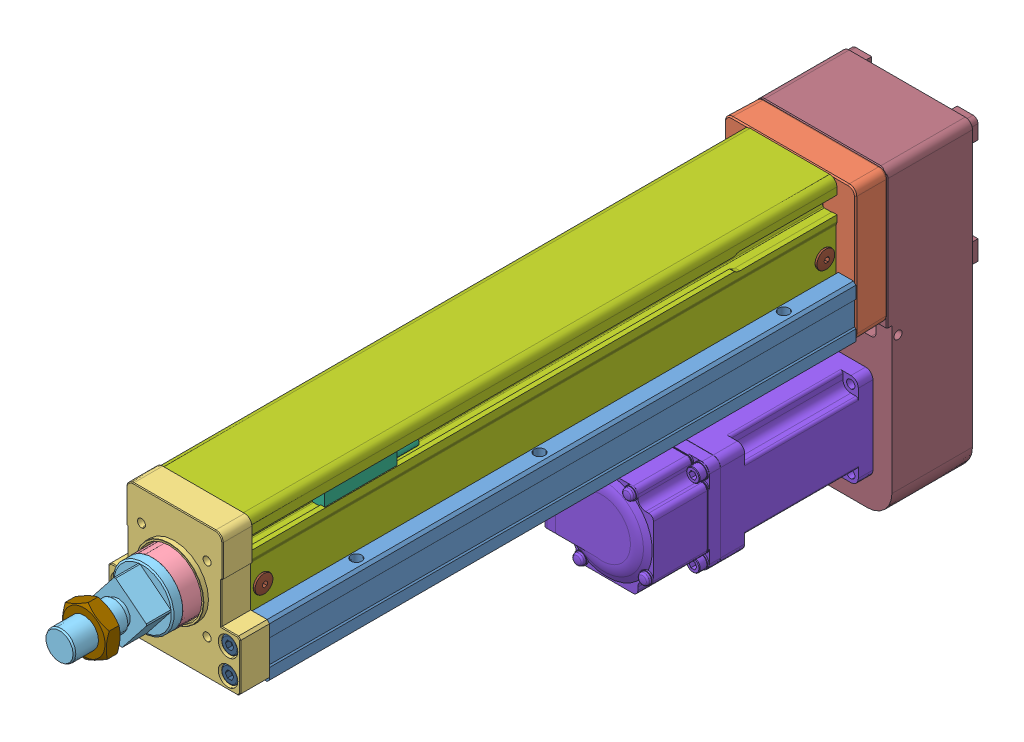
SolidWorks assembly Y5-BM-100W, configuration Default. Lengths in mm.
Overall size (128.79 125.85 350).
25 component instances, 14 part files, 57 mates.
Components (placement in the parent):
- 底座GY5^Y5-BM-100W-1: 底座GY5^Y5-BM-100W [默认] at (172.2343 500.0265 205.4117) x (1 0 0) z (0 -1 0) size (54 240 25) (virtual)
- 丝杆座板GY5^Y5-BM-100W-1: 丝杆座板GY5^Y5-BM-100W [默认] at (172.2343 515.5765 191.9117) size (54.09 55.09 28) (virtual)
- 轴承座Y5^Y5-BM-100W-1: 轴承座Y5^Y5-BM-100W [Default] at (172.2343 516.7765 445.4117) size (54 54 22) (virtual)
- 推杆Y5^Y5-BM-100W-1: 推杆Y5^Y5-BM-100W [Default] at (172.2343 516.7765 316.4117) x (-0.030388 -0.999538 0) z (-0.999538 0.030388 0) size (25 150 25) (virtual)
- 螺纹连接头Y5^Y5-BM-100W-1: 螺纹连接头Y5^Y5-BM-100W [Default] at (172.2343 516.7765 470.4117) x (-0.620248 -0.784406 0) z (0 0 -1) size (25 25 47) (virtual)
- 磁性感应开关^Y5-BM-100W-2: 磁性感应开关^Y5-BM-100W [默认] at (153.1454 533.4018 308.9117) x (-1 0 0) z (0 0 -1) size (5 6.3 39.5) (virtual)
- 上盖Y5^Y5-BM-100W-1: 上盖Y5^Y5-BM-100W [Default] at (153.6454 513.9765 205.4117) size (38.57 34 240) (virtual)
- 松下100W电机MSMF012L1U2^Y5-BM-100W-1: 松下100W电机MSMF012L1U2^Y5-BM-100W [默认] at (172.2343 447.7765 190.4117) x (0 0 -1) z (0 1 0) size (118.87 120.84 38.2) (virtual)
- 磁性感应开关^Y5-BM-100W-3: 磁性感应开关^Y5-BM-100W [默认] at (153.1454 533.4018 269.4117) x (-1 0 0) z (0 0 -1) size (5 6.3 39.5) (virtual)
- 磁性感应开关^Y5-BM-100W-4: 磁性感应开关^Y5-BM-100W [默认] at (191.3174 533.4018 385.4117) x (1 0 0) z (0 0 -1) size (5 6.3 39.5) (virtual)
- 六角薄螺母M12×1.25^Y5-BM-100W-1: 六角薄螺母M12×1.25^Y5-BM-100W [默认] at (172.2343 516.7765 494.4117) x (0.828588 -0.559859 0) z (0 0 1) size (20.78 18 6) (virtual)
- hexagon socket head cap screws gb-6: hexagon socket head cap screws gb [GB_FASTENER_SCREWS_HSHCS M4X12-N] at (194.2343 504.2765 456.8117) x (0 0 -1) z (1 0 0) size (16 7 7)
- hexagon socket head cap screws gb-7: hexagon socket head cap screws gb [GB_FASTENER_SCREWS_HSHCS M4X12-N] at (194.2343 493.7765 456.8117) x (0 0 -1) z (1 0 0) size (16 7 7)
- hexagon socket head cap screws gb-8: hexagon socket head cap screws gb [GB_FASTENER_SCREWS_HSHCS M4X12-N] at (150.2343 493.7765 456.8117) x (0 0 -1) z (1 0 0) size (16 7 7)
- hexagon socket head cap screws gb-9: hexagon socket head cap screws gb [GB_FASTENER_SCREWS_HSHCS M4X12-N] at (150.2343 504.2765 456.8117) x (0 0 -1) z (1 0 0) size (16 7 7)
- 内六角螺丝M3X5^Y5-BM-100W-1: 内六角螺丝M3X5^Y5-BM-100W [默认] at (186.1785 516.7765 210.4117) x (0 -1 0) z (0 0 1) size (7.5 6.19 7.5) (virtual)
- 内六角螺丝M3X5^Y5-BM-100W-2: 内六角螺丝M3X5^Y5-BM-100W [默认] at (186.1785 516.7765 440.4117) x (0 -0.21215 -0.977237) z (0 -0.977237 0.21215) size (7.5 6.19 7.5) (virtual)
- 内六角螺丝M3X5^Y5-BM-100W-3: 内六角螺丝M3X5^Y5-BM-100W [默认] at (158.2843 516.7765 440.4117) x (0 0.554408 0.832245) z (0 -0.832245 0.554408) size (7.5 6.19 7.5) (virtual)
- 内六角螺丝M3X5^Y5-BM-100W-4: 内六角螺丝M3X5^Y5-BM-100W [默认] at (158.2843 516.7765 210.4117) x (0 -0.497668 -0.867368) z (0 0.867368 -0.497668) size (7.5 6.19 7.5) (virtual)
- 304电机盖板Y5^Y5-BM-100W-1: 304电机盖板Y5^Y5-BM-100W [默认] at (172.2343 480.0265 157.4117) x (-1 0 0) z (0 -1 0) size (51.5 1 123.5) (virtual)
- 电机板Y5-BLRM-P38^Y5-BM-100W-1: 电机板Y5-BLRM-P38^Y5-BM-100W [默认] at (171.4843 468.5765 205.4117) x (0 0 1) z (-1 0 0) size (38 125.5 53.5) (virtual)
- hexagon socket button head screws gb-7: hexagon socket button head screws gb [GB_SOCKET_TYPE7 M3X6-N] at (159.7343 423.7765 154.7617) x (0 0 1) z (-1 0 0) size (7.65 5.7 5.7)
- hexagon socket button head screws gb-8: hexagon socket button head screws gb [GB_SOCKET_TYPE7 M3X6-N] at (184.7343 423.7765 154.7617) x (0 0 1) z (-1 0 0) size (7.65 5.7 5.7)
- hexagon socket button head screws gb-9: hexagon socket button head screws gb [GB_SOCKET_TYPE7 M3X6-N] at (159.7343 536.7765 154.7617) x (0 0 1) z (-1 0 0) size (7.65 5.7 5.7)
- hexagon socket button head screws gb-10: hexagon socket button head screws gb [GB_SOCKET_TYPE7 M3X6-N] at (184.7343 536.7765 154.7617) x (0 0 1) z (-1 0 0) size (7.65 5.7 5.7)
Mates (geometry in assembly coordinates):
- 同心129: concentric: cylinder of 推杆Y5^Y5-BM-100W-1 through (172.2343 516.7765 466.4117) axis (0 0 -1) radius 8.5; cylinder of 螺纹连接头Y5^Y5-BM-100W-1 through (172.2343 516.7765 457.4117) axis (0 0 1) radius 10
- 重合133: coincident: plane of 推杆Y5^Y5-BM-100W-1 through (172.2343 516.7765 466.4117) normal (0 0 1); plane of 螺纹连接头Y5^Y5-BM-100W-1 through (172.2343 516.7765 466.4117) normal (0 0 -1)
- 同心133: concentric: cylinder of 底座GY5^Y5-BM-100W-1 through (194.2343 493.7765 445.4117) axis (0 0 1) radius 1.65; cylinder of 轴承座Y5^Y5-BM-100W-1 through (194.2343 493.7765 457.4117) axis (0 0 1) radius 2.25
- 重合134: coincident: plane of 底座GY5^Y5-BM-100W-1 through (167.2343 487.8265 445.4117) normal (0 0 1); plane of 轴承座Y5^Y5-BM-100W-1 through (172.2343 516.7765 445.4117) normal (0 0 -1)
- 同心136: concentric: cylinder of 底座GY5^Y5-BM-100W-1 through (150.2343 504.2765 445.4117) axis (0 0 1) radius 1.65; cylinder of 轴承座Y5^Y5-BM-100W-1 through (150.2343 504.2765 457.4117) axis (0 0 1) radius 2.25
- 重合143: coincident: plane of 底座GY5^Y5-BM-100W-1 through (167.2343 487.8265 445.4117) normal (0 0 1); plane of 上盖Y5^Y5-BM-100W-1 through (158.1567 536.5769 445.4117) normal (0 0 1)
- 重合144: coincident: plane of 底座GY5^Y5-BM-100W-1 through (190.0843 508.7765 445.4117) normal (0 1 0); plane of 上盖Y5^Y5-BM-100W-1 through (191.1785 508.7765 445.4117) normal (0 -1 0)
- 宽度31: width: plane of 磁性感应开关^Y5-BM-100W-2 through (158.1454 536.5518 338.4117) normal (0 1 0); plane of 磁性感应开关^Y5-BM-100W-2 through (158.1454 530.2518 308.9117) normal (0 -1 0); plane of 上盖Y5^Y5-BM-100W-1 through (158.1567 529.7267 445.4117) normal (0 1 0); plane of 上盖Y5^Y5-BM-100W-1 through (154.9454 537.0769 445.4117) normal (0 -1 0)
- 重合148: coincident: plane of 磁性感应开关^Y5-BM-100W-2 through (154.9454 536.5518 338.4117) normal (-1 0 0); plane of 上盖Y5^Y5-BM-100W-1 through (154.9454 536.0769 445.4117) normal (1 0 0)
- 重合1579: coincident: plane of 底座GY5^Y5-BM-100W-1 through (154.3843 512.7765 445.4117) normal (-1 0 0); plane of 上盖Y5^Y5-BM-100W-1 through (154.3843 527.7267 445.4117) normal (1 0 0)
- 重合1583: coincident: line of 磁性感应开关^Y5-BM-100W-2 through (158.1454 536.5518 338.4117) axis (0 0 -1); plane of 磁性感应开关^Y5-BM-100W-3 through (158.1454 533.4018 269.4117) normal (1 0 0)
- 重合1586: coincident: plane of 磁性感应开关^Y5-BM-100W-2 through (158.1454 536.5518 338.4117) normal (0 1 0); plane of 磁性感应开关^Y5-BM-100W-3 through (158.1454 536.5518 298.9117) normal (0 1 0)
- 重合1603: coincident: plane of 磁性感应开关^Y5-BM-100W-2 through (155.6454 533.4018 298.9117) normal (0 0 -1); plane of 磁性感应开关^Y5-BM-100W-3 through (158.1454 530.2518 298.9117) normal (0 0 1)
- 距离9: distance = 30.5 mm: plane of 磁性感应开关^Y5-BM-100W-4 through (186.3174 536.5518 414.9117) normal (0 0 1); plane of 轴承座Y5^Y5-BM-100W-1 through (172.2343 516.7765 445.4117) normal (0 0 -1)
- 同心1661: concentric: cylinder of 底座GY5^Y5-BM-100W-1 through (194.3343 506.7765 205.4117) axis (0 0 -1) radius 1.65; cylinder of 丝杆座板GY5^Y5-BM-100W-1 through (194.3343 506.7765 192.4117) axis (0 0 -1) radius 4
- 同心1662: concentric: cylinder of 底座GY5^Y5-BM-100W-1 through (150.1343 506.7765 205.4117) axis (0 0 -1) radius 1.65; cylinder of 丝杆座板GY5^Y5-BM-100W-1 through (150.1343 506.7765 192.4117) axis (0 0 -1) radius 2.4
- 重合1605: coincident: plane of 底座GY5^Y5-BM-100W-1 through (167.2343 487.8265 205.4117) normal (0 0 -1); plane of 丝杆座板GY5^Y5-BM-100W-1 through (172.2343 515.5765 205.4117) normal (0 0 1)
- 距离11: distance = 64 mm: plane of 磁性感应开关^Y5-BM-100W-3 through (158.1454 536.5518 269.4117) normal (0 0 -1); plane of 丝杆座板GY5^Y5-BM-100W-1 through (172.2343 515.5765 205.4117) normal (0 0 1)
- 同心1672: concentric: cylinder of 螺纹连接头Y5^Y5-BM-100W-1 through (172.2343 516.7765 504.4117) axis (0 0 -1) radius 6; cylinder of 六角薄螺母M12×1.25^Y5-BM-100W-1 through (172.2343 516.7765 488.4117) axis (0 0 1) radius 5.3235
- 距离12: distance = 8 mm: plane of 螺纹连接头Y5^Y5-BM-100W-1 through (172.2343 516.7765 480.4117) normal (0 0 1); plane of 六角薄螺母M12×1.25^Y5-BM-100W-1 through (162.8901 512.2283 488.4117) normal (0 0 -1)
- 重合1616: coincident: plane of 上盖Y5^Y5-BM-100W-1 through (189.5174 529.7267 445.4117) normal (-1 0 0); plane of 磁性感应开关^Y5-BM-100W-4 through (189.5174 530.2518 414.9117) normal (1 0 0)
- 宽度33: width: plane of 上盖Y5^Y5-BM-100W-1 through (189.5174 530.7267 445.4117) normal (0 1 0); plane of 上盖Y5^Y5-BM-100W-1 through (189.5174 536.0769 445.4117) normal (0 -1 0); plane of 磁性感应开关^Y5-BM-100W-4 through (191.3174 535.9018 414.9117) normal (0 1 0); plane of 磁性感应开关^Y5-BM-100W-4 through (189.5174 530.9018 414.9117) normal (0 -1 0)
- 同心1673: concentric: cylinder of 轴承座Y5^Y5-BM-100W-1 through (172.2343 516.7765 457.4117) axis (0 0 -1) radius 13.25; cylinder of 推杆Y5^Y5-BM-100W-1 through (172.2343 516.7765 466.4117) axis (0 0 -1) radius 12.5
- 距离13: distance = 47 mm: plane of 螺纹连接头Y5^Y5-BM-100W-1 through (172.2343 516.7765 504.4117) normal (0 0 1); plane of 轴承座Y5^Y5-BM-100W-1 through (172.2343 516.7765 457.4117) normal (0 0 1)
- 同心1674: concentric: cylinder of 轴承座Y5^Y5-BM-100W-1 through (194.2343 504.2765 457.4117) axis (0 0 1) radius 2.25; cylinder of hexagon socket head cap screws gb-6 through (194.2343 504.2765 440.8117) axis (0 0 1) radius 2
- 重合1618: coincident: plane of 轴承座Y5^Y5-BM-100W-1 through (196.4843 504.2765 452.8117) normal (0 0 1); plane of hexagon socket head cap screws gb-6 through (194.2343 504.2765 452.8117) normal (0 0 -1)
- 同心1675: concentric: cylinder of 轴承座Y5^Y5-BM-100W-1 through (194.2343 493.7765 457.4117) axis (0 0 1) radius 4; cylinder of hexagon socket head cap screws gb-7 through (194.2343 493.7765 440.8117) axis (0 0 1) radius 2
- 重合1619: coincident: plane of 轴承座Y5^Y5-BM-100W-1 through (196.4843 493.7765 452.8117) normal (0 0 1); plane of hexagon socket head cap screws gb-7 through (194.2343 493.7765 452.8117) normal (0 0 -1)
- 同心1676: concentric: cylinder of 轴承座Y5^Y5-BM-100W-1 through (150.2343 493.7765 457.4117) axis (0 0 1) radius 2.25; cylinder of hexagon socket head cap screws gb-8 through (150.2343 493.7765 440.8117) axis (0 0 1) radius 2
- 重合1620: coincident: plane of 轴承座Y5^Y5-BM-100W-1 through (152.4843 493.7765 452.8117) normal (0 0 1); plane of hexagon socket head cap screws gb-8 through (150.2343 493.7765 452.8117) normal (0 0 -1)
- 同心1677: concentric: cylinder of 轴承座Y5^Y5-BM-100W-1 through (150.2343 504.2765 457.4117) axis (0 0 1) radius 2.25; cylinder of hexagon socket head cap screws gb-9 through (150.2343 504.2765 440.8117) axis (0 0 1) radius 2
- 重合1621: coincident: plane of 轴承座Y5^Y5-BM-100W-1 through (152.4843 504.2765 452.8117) normal (0 0 1); plane of hexagon socket head cap screws gb-9 through (150.2343 504.2765 452.8117) normal (0 0 -1)
- 同心1678: concentric: cylinder of 丝杆座板GY5^Y5-BM-100W-1 through (189.9843 516.7765 210.4117) axis (1 0 0) radius 1.25; cylinder of 内六角螺丝M3X5^Y5-BM-100W-1 through (186.1785 516.7765 210.4117) axis (-1 0 0) radius 1.5
- 重合1622: coincident: plane of 上盖Y5^Y5-BM-100W-1 through (191.1785 526.1852 445.4117) normal (1 0 0); circle of 内六角螺丝M3X5^Y5-BM-100W-1
- 同心1679: concentric: cylinder of 上盖Y5^Y5-BM-100W-1 through (153.2843 516.7765 440.4117) axis (-1 0 0) radius 1.75; cylinder of 内六角螺丝M3X5^Y5-BM-100W-2 through (186.1785 516.7765 440.4117) axis (-1 0 0) radius 1.5
- 重合1623: coincident: plane of 上盖Y5^Y5-BM-100W-1 through (191.1785 526.1852 445.4117) normal (1 0 0); plane of 内六角螺丝M3X5^Y5-BM-100W-2 through (191.1785 516.7765 440.4117) normal (-1 0 0)
- 重合1624: coincident: plane of 上盖Y5^Y5-BM-100W-1 through (153.2843 526.1852 445.4117) normal (-1 0 0); plane of 内六角螺丝M3X5^Y5-BM-100W-3 through (153.2843 516.7765 440.4117) normal (1 0 0)
- 同心1680: concentric: cylinder of 上盖Y5^Y5-BM-100W-1 through (153.2843 516.7765 440.4117) axis (-1 0 0) radius 1.75; cylinder of 内六角螺丝M3X5^Y5-BM-100W-3 through (158.2843 516.7765 440.4117) axis (1 0 0) radius 1.5
- 同心1681: concentric: cylinder of 上盖Y5^Y5-BM-100W-1 through (153.2843 516.7765 210.4117) axis (-1 0 0) radius 1.75; cylinder of 内六角螺丝M3X5^Y5-BM-100W-4 through (158.2843 516.7765 210.4117) axis (1 0 0) radius 1.5
- 重合1625: coincident: plane of 上盖Y5^Y5-BM-100W-1 through (153.2843 526.1852 445.4117) normal (-1 0 0); plane of 内六角螺丝M3X5^Y5-BM-100W-4 through (153.2843 516.7765 210.4117) normal (1 0 0)
- 同心1691: concentric: cylinder of 304电机盖板Y5^Y5-BM-100W-1 through (159.7343 423.7765 156.4117) axis (0 0 -1) radius 1.7; cylinder of hexagon socket button head screws gb-7 through (159.7343 423.7765 162.4117) axis (0 0 -1) radius 1.5
- 重合1631: coincident: plane of 304电机盖板Y5^Y5-BM-100W-1 through (147.4843 500.7765 156.4117) normal (0 0 -1); plane of hexagon socket button head screws gb-7 through (159.7343 423.7765 156.4117) normal (0 0 1)
- 同心1692: concentric: cylinder of 304电机盖板Y5^Y5-BM-100W-1 through (184.7343 423.7765 156.4117) axis (0 0 -1) radius 1.7; cylinder of hexagon socket button head screws gb-8 through (184.7343 423.7765 162.4117) axis (0 0 -1) radius 1.5
- 重合1632: coincident: plane of 304电机盖板Y5^Y5-BM-100W-1 through (147.4843 500.7765 156.4117) normal (0 0 -1); plane of hexagon socket button head screws gb-8 through (184.7343 423.7765 156.4117) normal (0 0 1)
- 同心1693: concentric: cylinder of 304电机盖板Y5^Y5-BM-100W-1 through (159.7343 536.7765 156.4117) axis (0 0 -1) radius 1.7; cylinder of hexagon socket button head screws gb-9 through (159.7343 536.7765 162.4117) axis (0 0 -1) radius 1.5
- 重合1633: coincident: plane of 304电机盖板Y5^Y5-BM-100W-1 through (147.4843 500.7765 156.4117) normal (0 0 -1); plane of hexagon socket button head screws gb-9 through (159.7343 536.7765 156.4117) normal (0 0 1)
- 同心1694: concentric: cylinder of 304电机盖板Y5^Y5-BM-100W-1 through (184.7343 536.7765 156.4117) axis (0 0 -1) radius 1.7; cylinder of hexagon socket button head screws gb-10 through (184.7343 536.7765 162.4117) axis (0 0 -1) radius 1.5
- 重合1634: coincident: plane of 304电机盖板Y5^Y5-BM-100W-1 through (147.4843 500.7765 156.4117) normal (0 0 -1); plane of hexagon socket button head screws gb-10 through (184.7343 536.7765 156.4117) normal (0 0 1)
- 同心1695: concentric: cylinder of 丝杆座板GY5^Y5-BM-100W-1 through (172.2343 516.7765 192.4117) axis (0 0 -1) radius 16; cylinder of 电机板Y5-BLRM-P38^Y5-BM-100W-1 through (172.2343 516.7765 192.4117) axis (0 0 -1) radius 16
- 重合1635: coincident: plane of 丝杆座板GY5^Y5-BM-100W-1 through (172.2343 516.7765 192.4117) normal (0 0 -1); plane of 电机板Y5-BLRM-P38^Y5-BM-100W-1 through (171.4843 468.5765 192.4117) normal (0 0 1)
- 重合1636: coincident: plane of 304电机盖板Y5^Y5-BM-100W-1 through (147.4843 500.7765 157.4117) normal (0 0 1); plane of 电机板Y5-BLRM-P38^Y5-BM-100W-1 through (171.4843 468.5765 157.4117) normal (0 0 -1)
- 同心1697: concentric: cylinder of hexagon socket button head screws gb-9 through (159.7343 536.7765 162.4117) axis (0 0 -1) radius 1.5; cylinder of 电机板Y5-BLRM-P38^Y5-BM-100W-1 through (159.7343 536.7765 157.4117) axis (0 0 -1) radius 1.25
- 同心1698: concentric: cylinder of hexagon socket button head screws gb-8 through (184.7343 423.7765 162.4117) axis (0 0 -1) radius 1.5; cylinder of 电机板Y5-BLRM-P38^Y5-BM-100W-1 through (184.7343 423.7765 157.4117) axis (0 0 -1) radius 1.25
- 同心1700: concentric: cylinder of 松下100W电机MSMF012L1U2^Y5-BM-100W-1 through (172.2343 447.7765 165.4117) axis (0 0 1) radius 4; cylinder of 电机板Y5-BLRM-P38^Y5-BM-100W-1 through (172.2343 447.7765 179.4117) axis (0 0 1) radius 15
- 重合1637: coincident: plane of 松下100W电机MSMF012L1U2^Y5-BM-100W-1 through (156.2343 463.7765 190.4117) normal (0 0 -1); plane of 电机板Y5-BLRM-P38^Y5-BM-100W-1 through (171.4843 468.5765 190.4117) normal (0 0 1)
- 同心1702: concentric: cylinder of 丝杆座板GY5^Y5-BM-100W-1 through (172.2343 537.2765 192.4117) axis (0 0 -1) radius 1.65; circle of 电机板Y5-BLRM-P38^Y5-BM-100W-1
- 同心1703: concentric: cylinder of 松下100W电机MSMF012L1U2^Y5-BM-100W-1 through (156.3244 463.6864 196.4117) axis (0 0 1) radius 1.7; cylinder of 电机板Y5-BLRM-P38^Y5-BM-100W-1 through (156.3244 463.6864 192.4117) axis (0 0 1) radius 1.25
